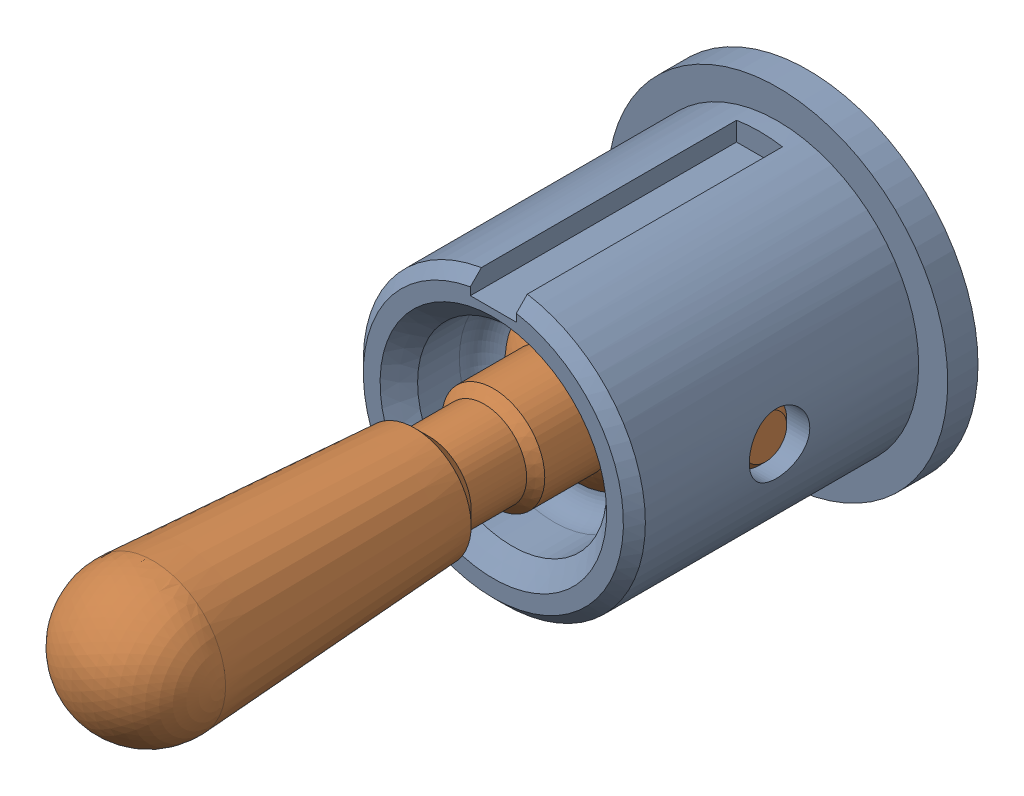
SolidWorks assembly MS Toggle Switch Sealed 3-Position Ref v1, configuration Default. Lengths in mm.
Overall size (14.29 14.29 30.73).
2 component instances, 2 part files, 0 mates.
Components (placement in the parent):
- Toggle Threads Sealed Ref-1: Toggle Threads Sealed Ref [Default] at (41.275 12.7 -6.1811) x (-1 0 0) z (0 0 1) size (14.29 14.29 13.21)
- Toggle Lever Sealed Ref-1: Toggle Lever Sealed Ref [Default] at (41.275 12.7 -6.1811) x (-1 0 0) z (0 0 1) size (10.67 7.94 27.59)
